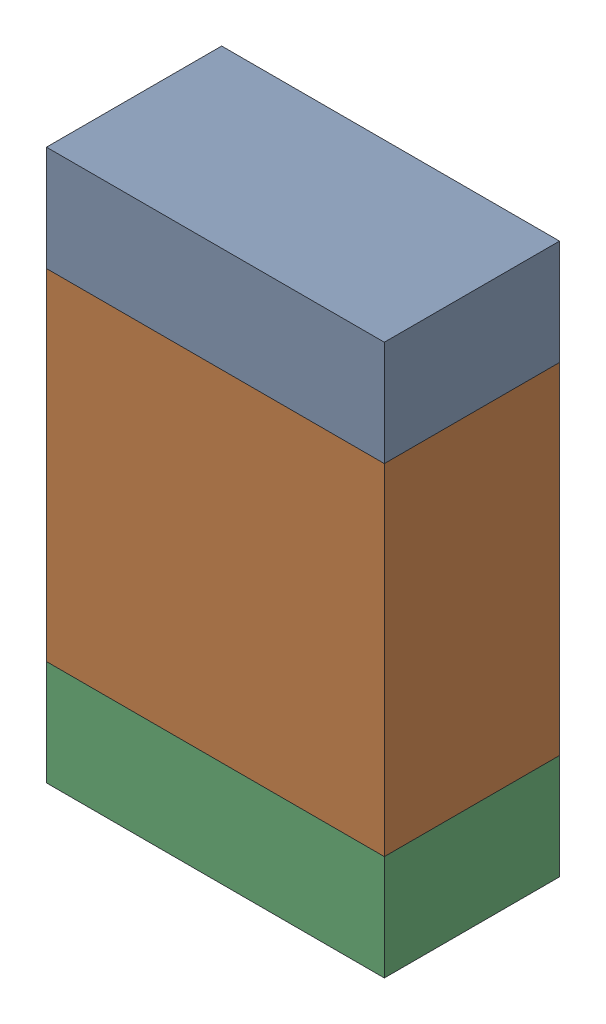
SolidWorks assembly R3-2, configuration Default. Lengths in mm.
Overall size (1.35 2.2 0.7).
6 component instances, 2 part files, 0 mates.
Components (placement in the parent):
- 959207304-2-1: 959207304-2 [Default] at (114.1729 78.1061 0) size (1.35 0.42 0.7)
  - Extruded-70-1: Extruded-70 [Default] at origin size (1.35 0.42 0.7)
- 959207440-2-1: 959207440-2 [Default] at (114.1729 77.2161 0) size (1.35 1.36 0.7)
  - Extruded-71-1: Extruded-71 [Default] at origin size (1.35 1.36 0.7)
- 959207304-2-2: 959207304-2 [Default] at (114.1729 76.3261 0) size (1.35 0.42 0.7)
  - Extruded-70-1: Extruded-70 [Default] at origin size (1.35 0.42 0.7)
